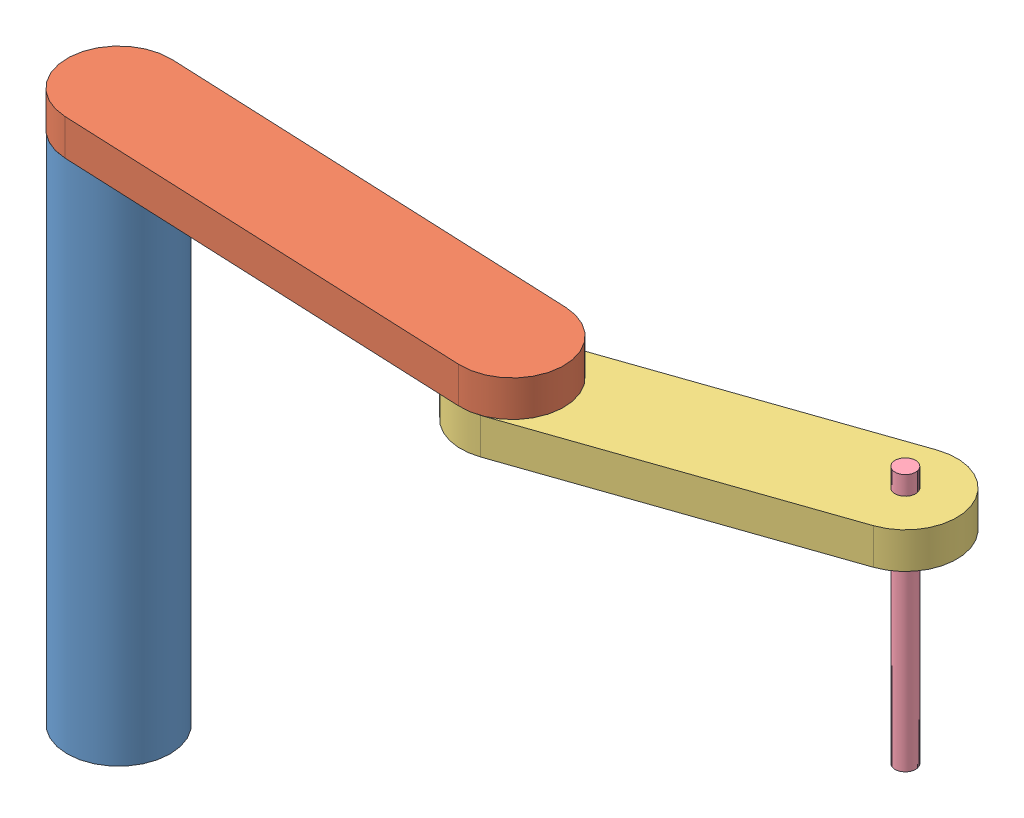
SolidWorks assembly Assem1, configuration Default. Lengths in mm.
Overall size (1597.75 1070 450.37).
4 component instances, 4 part files, 8 mates.
Components (placement in the parent):
- base-1: base [Default] at (-3.628 0 1155.1179) size (200 1000 200)
- L1-1: L1 [Default] at (-3.628 1000 1155.1179) x (0.999063 0 0.043279) z (-0.043279 0 0.999063) size (1000 90 200)
- L2-1: L2 [Default] at (795.6224 930 1189.7408) x (0.945136 0 -0.326677) z (0.326677 0 0.945136) size (800 70 200)
- D3-1: D3 [Default] at (1362.7041 536.3781 993.7346) x (0.941707 0 0.336433) z (-0.336433 0 0.941707) size (40 500 40)
Mates (geometry in assembly coordinates):
- Coincident1: coincident aligned: plane of base-1 through (-3.628 0 1155.1179) normal (0 1 0)
- Coincident2: coincident anti-aligned: plane of base-1 through (-3.628 1000 1155.1179) normal (0 1 0); plane of L1-1 through (-3.628 1000 1155.1179) normal (0 -1 0)
- Concentric1: concentric aligned: cylinder of base-1 through (-3.628 980 1155.1179) axis (0 1 0) radius 10; cylinder of L1-1 through (-3.628 980 1155.1179) axis (0 1 0) radius 10
- Coincident3: coincident anti-aligned: plane of L1-1 through (-3.628 1000 1155.1179) normal (0 -1 0); plane of L2-1 through (795.6224 1000 1189.7408) normal (0 1 0)
- Concentric2: concentric aligned: cylinder of L1-1 through (795.6224 980 1189.7408) axis (0 1 0) radius 10; cylinder of L2-1 through (795.6224 980 1189.7408) axis (0 1 0) radius 10
- Concentric10: concentric anti-aligned: cylinder of L2-1 through (1362.7041 930 993.7346) axis (0 1 0) radius 20; cylinder of D3-1 through (1362.7041 1036.3781 993.7346) axis (0 -1 0) radius 20
- LimitDistance3: limit distance = 36.3781 mm aligned: plane of D3-1 through (1362.7041 1036.3781 993.7346) normal (0 1 0); plane of L2-1 through (795.6224 1000 1189.7408) normal (0 1 0)
- LimitDistance4: limit distance = 393.6219 mm aligned: plane of D3-1 through (1362.7041 536.3781 993.7346) normal (0 -1 0); plane of L2-1 through (795.6224 930 1189.7408) normal (0 -1 0)
